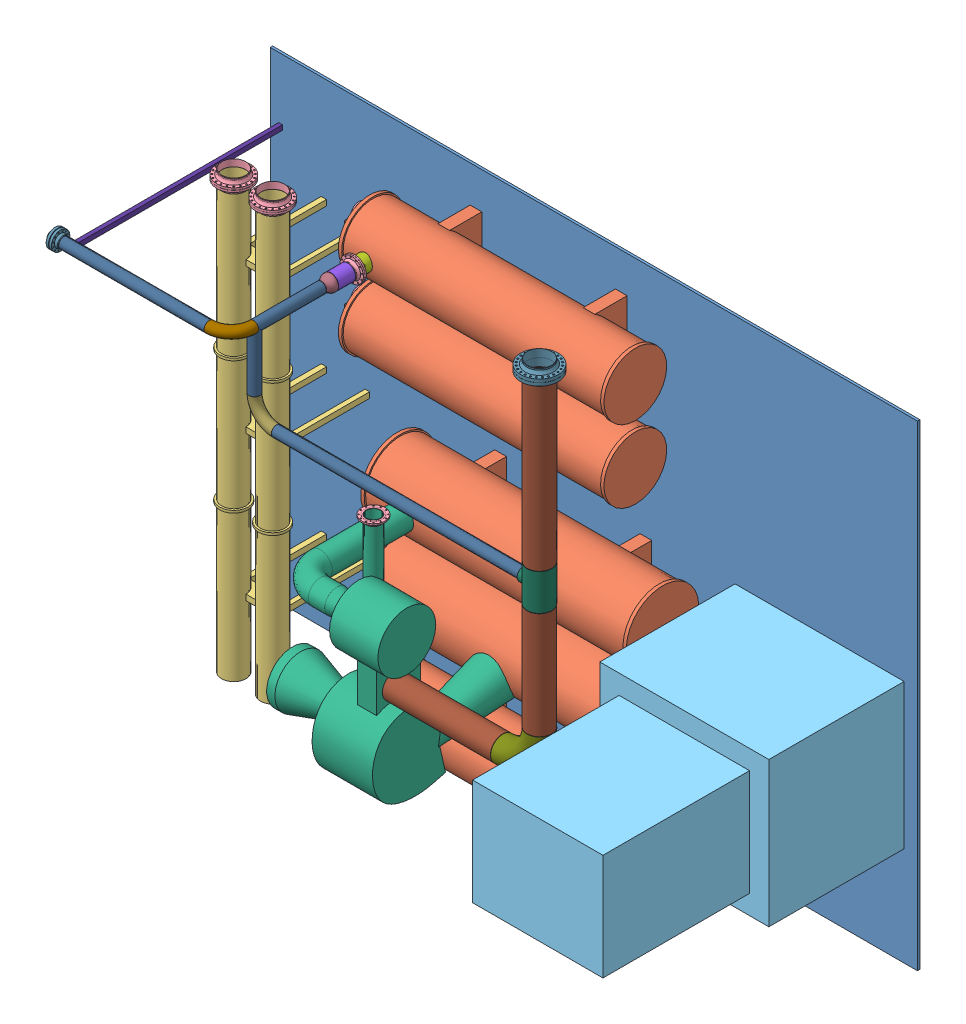
SolidWorks assembly KOMPRESOR-2 SKLOP, configuration Default. Lengths in mm.
Overall size (13601 11029 5885).
47 component instances, 18 part files, 71 mates.
Components (placement in the parent):
- Part2^Assem1-1: Part2^Assem1 [Default] at (-624 250 -240.5401) size (13400 9858 50)
- Rezervoar 1500-1: Rezervoar 1500 [1300] at (150 -3000 714.4599) x (1 0 0) z (0 -1 0) size (5800 1605 1300)
- Rezervoar 1500-2: Rezervoar 1500 [Default] at (150 867 659.4599) x (1 0 0) z (0 -1 0) size (5800 1650 1500)
- Rezervoar 1500-3: Rezervoar 1500 [Default] at (150 -899 659.4599) x (1 0 0) z (0 -1 0) size (5800 1650 1500)
- Rezervoar 1500-4: Rezervoar 1500 [1300] at (-360 3500 714.4599) x (1 0 0) z (0 -1 0) size (5800 1605 1300)
- Rezervoar 1500-5: Rezervoar 1500 [1300] at (-360 5000 714.4599) x (1 0 0) z (0 -1 0) size (5800 1605 1300)
- Kolektori-1: Kolektori [Default] at (-4165 1085.73 1669.4599) x (0 -1 0) z (-1 0 0) size (8880 2204 1392)
- welding neck flange-1: welding neck flange [WNeck Flange 150-NPS8] at (-2898.476 -3170 789.4599) x (0 0 1) z (-1 0 0) size (342.9 342.9 111.61)
- welding neck flange-2: welding neck flange [WNeck Flange 150-NPS8] at (-2898.476 -2830 639.4599) x (0 0 1) z (-1 0 0) size (342.9 342.9 111.61)
- welding neck flange-3: welding neck flange [WNeck Flange 150-NPS8] at (-3408.476 3330 789.4599) x (0 0 1) z (-1 0 0) size (342.9 342.9 111.61)
- welding neck flange-5: welding neck flange [WNeck Flange 150-NPS8] at (-3408.476 3670 639.4599) x (0 0 1) z (-1 0 0) size (342.9 342.9 111.61)
- welding neck flange-6: welding neck flange [WNeck Flange 150-NPS8] at (-3408.476 4830 789.4599) x (0 0 1) z (-1 0 0) size (342.9 342.9 111.61)
- welding neck flange-7: welding neck flange [WNeck Flange 150-NPS8] at (-3408.476 5170 639.4599) x (0 0 1) z (-1 0 0) size (342.9 342.9 111.61)
- welding neck flange-8: welding neck flange [WNeck Flange 150-NPS6] at (-2898.476 -1069 659.46) x (0 0 1) z (-1 0 0) size (279.4 279.4 98.91)
- welding neck flange-9: welding neck flange [WNeck Flange 150-NPS6] at (-2898.476 -729 659.4598) x (0 0 1) z (-1 0 0) size (279.4 279.4 98.91)
- welding neck flange-10: welding neck flange [WNeck Flange 150-NPS6] at (-2898.476 697 659.46) x (0 0 1) z (-1 0 0) size (279.4 279.4 98.91)
- welding neck flange-11: welding neck flange [WNeck Flange 150-NPS6] at (-2898.476 1037 659.4598) x (0 0 1) z (-1 0 0) size (279.4 279.4 98.91)
- Postolje-1: Postolje [Default] at (0 0 2519.4599) (suppressed, hidden)
- MOTOR-1: MOTOR [Default] at (-624 250 -240.5401) size (3500 3000 5835)
- Kompresorsko kolo-1: Kompresorsko kolo [Default] at (0 0.002 -78.038) x (0 0 -1) z (1 0 0) size (3486.15 4337.68 5940.11)
- welding neck flange-25: welding neck flange [WNeck Flange 150-NPS20] at (-4969 5524.206 1669.4599) x (1 0 0) z (0 1 0) size (698.5 698.5 154.28)
- welding neck flange-26: welding neck flange [WNeck Flange 150-NPS20] at (-4165 5524.206 1669.4599) x (1 0 0) z (0 1 0) size (698.5 698.5 154.28)
- welding neck flange-27: welding neck flange [WNeck Flange 150-NPS20] at (-4969 5527.254 1669.4599) x (1 0 0) z (0 -1 0) size (698.5 698.5 154.28)
- welding neck flange-28: welding neck flange [WNeck Flange 150-NPS20] at (-4165 5525.73 1669.4599) x (1 0 0) z (0 -1 0) size (698.5 698.5 154.28)
- welding neck flange-30: welding neck flange [WNeck Flange 150-NPS12] at (-593 2398.478 3154.4599) x (1 0 0) z (0 1 0) size (482.6 482.6 124.31)
- Part2^KOMPRESOR-2 SKLOP-1: Part2^KOMPRESOR-2 SKLOP [Default] at (-360 5000 714.4599) x (-1 0 0) z (0 0 1) size (324.8 324.8 850)
- welding neck flange-33: welding neck flange [WNeck Flange 150-NPS12] at (-2600 5000 1562.9359) size (482.6 482.6 124.31)
- routeAssy3-KOMPRESOR-2 SKLOP-1: routeAssy3-KOMPRESOR-2 SKLOP [Default] at origin size (10012.35 7738.21 2713.51)
  - welding neck flange-1: welding neck flange [WNeck Flange 150-NPS12] at (-2600 5000 1565.9839) x (0.923728 0.383049 0) z (0 0 -1) size (482.6 482.6 124.31)
  - 12inSchedule60-routeAssy3-KOMPRESOR-2 SKLOP-1: 12inSchedule60-routeAssy3-KOMPRESOR-2 SKLOP [12 in, Schedule 60] at (-2600 5000 1678.7599) x (0.707107 0.707107 0) z (0 0 1) size (323.85 323.85 348.4) (virtual)
  - 12inSchedule60_2-routeAssy3-KOMPRESOR-2 SKLOP-1: 12inSchedule60_2-routeAssy3-KOMPRESOR-2 SKLOP [Pipe 12 in, Sch 60] at (-2600 5000 3630.2599) x (0.707107 0.707107 0) z (0 0 -1) size (510.17 510.17 566.67) (virtual)
  - 8inSchedule20_1-routeAssy3-KOMPRESOR-2 SKLOP-1: 8inSchedule20_1-routeAssy3-KOMPRESOR-2 SKLOP [8 in, Schedule 20, 5] at (-2600 5000 2230.3599) x (0.707107 0.707107 0) z (0 0 1) size (218.95 218.95 1408.24)
  - 8inSchedule20_1-routeAssy3-KOMPRESOR-2 SKLOP-2: 8inSchedule20_1-routeAssy3-KOMPRESOR-2 SKLOP [8 in, Schedule 20, 1] at (-3057.2 5000 4087.4599) x (0 0.707107 0.707107) z (-1 0 0) size (218.95 218.95 3010.4)
  - 20inSchedule60-routeAssy3-KOMPRESOR-2 SKLOP-1: 20inSchedule60-routeAssy3-KOMPRESOR-2 SKLOP [20 in, Schedule 60, 3] at (3300 7044.896 3609.4599) x (0.707107 0 0.707107) z (0 -1 0) size (508 508 3315.74)
  - 20inSchedule60-routeAssy3-KOMPRESOR-2 SKLOP-2: 20inSchedule60-routeAssy3-KOMPRESOR-2 SKLOP [20 in, Schedule 60, 1] at (2538 0 3609.4599) x (0 0.707107 0.707107) z (-1 0 0) size (508 508 2238)
  - 20inSchedule60-routeAssy3-KOMPRESOR-2 SKLOP-3: 20inSchedule60-routeAssy3-KOMPRESOR-2 SKLOP [20 in, Schedule 60, 2] at (3300 2967.1563 3609.4599) x (0.707107 0 0.707107) z (0 -1 0) size (508 508 2205.16)
  - 12inSchedule60_3-routeAssy3-KOMPRESOR-2 SKLOP-1: 12inSchedule60_3-routeAssy3-KOMPRESOR-2 SKLOP [Pipe 12 in, Sch 60] at (-2600 3805.3563 3609.4599) x (0.707107 0 0.707107) z (0 1 0) size (510.17 510.17 566.67)
  - 8inSchedule20_1-routeAssy3-KOMPRESOR-2 SKLOP-5: 8inSchedule20_1-routeAssy3-KOMPRESOR-2 SKLOP [8 in, Schedule 20, 2] at (-2142.8 3348.1563 3609.4599) x (0 0.707107 0.707107) z (1 0 0) size (218.95 218.95 5110.06)
  - 8inSchedule20_1-routeAssy3-KOMPRESOR-2 SKLOP-6: 8inSchedule20_1-routeAssy3-KOMPRESOR-2 SKLOP [8 in, Schedule 20] at (-2600 3805.3563 3609.4599) x (0.707107 0 0.707107) z (0 1 0) size (218.95 218.95 1194.64)
  - Backup of reducer-1: Backup of reducer [REDUCER 12 x 8] at (-2600 5000 2027.1599) x (0 0 1) z (0 1 0) size (223.2 323.85 323.85)
  - Backup of welding neck flange-1: Backup of welding neck flange [WNeck Flange 400-NPS8] at (-6184.952 5000 4087.4599) x (0 0 1) z (-1 0 0) size (381 381 133.71)
  - Backup of reducing outlet tee inch-2: Backup of reducing outlet tee inch [RTee Inch20x20x8Sch60] at (3300 3348.1563 3609.4599) x (0 -1 0) z (0 0 -1) size (782 596.74 508)
  - 90deg LR Inch Elbow-1: 90deg LR Inch Elbow [90L LR Inch 20 Sch60] at (2538 762 3609.4599) x (0 1 0) z (0 0 -1) size (1026.09 1026.09 508.2)
  - Backup of welding neck flange-8: Backup of welding neck flange [WNeck Flange 300-NPS20] at (3300 7208.472 3609.4599) x (1 0 0) z (0 -1 0) size (774.7 774.7 172.06)
  - Backup of welding neck flange-9: Backup of welding neck flange [WNeck Flange 300-NPS20] at (3300 7205.424 3609.4599) x (0 0 1) z (0 1 0) size (774.7 774.7 172.06)
  - Backup of welding neck flange-10: Backup of welding neck flange [WNeck Flange 400-NPS8] at (-6197.652 5000 4087.4599) x (0 1 0) z (1 0 0) size (381 381 133.71)
- Part1^KOMPRESOR-2 SKLOP-2: Part1^KOMPRESOR-2 SKLOP [Default] at (-624 250 -240.5401) size (78.44 98.05 4231.12)
Mates (geometry in assembly coordinates):
- Coincident1: coincident anti-aligned: plane of Part2^Assem1-1 through (-6124 -3550 -240.5401) normal (0 0 1); plane of Rezervoar 1500-1 through (-2518.9944 -3000 -240.5401) normal (0 0 -1)
- Coincident3: coincident anti-aligned: plane of Rezervoar 1500-4 through (-3028.9944 3500 -240.5401) normal (0 0 -1); plane of Part2^Assem1-1 through (-6124 -3550 -240.5401) normal (0 0 1)
- Coincident4: coincident anti-aligned: plane of Rezervoar 1500-2 through (-2518.9944 867 -240.5401) normal (0 0 -1); plane of Part2^Assem1-1 through (-6124 -3550 -240.5401) normal (0 0 1)
- Coincident5: coincident anti-aligned: plane of Rezervoar 1500-3 through (-2518.9944 -899 -240.5401) normal (0 0 -1); plane of Part2^Assem1-1 through (-6124 -3550 -240.5401) normal (0 0 1)
- Coincident6: coincident anti-aligned: plane of Rezervoar 1500-5 through (-3028.9944 5000 -240.5401) normal (0 0 -1); plane of Part2^Assem1-1 through (-6124 -3550 -240.5401) normal (0 0 1)
- Distance1: distance = 867 mm anti-aligned: plane of assembly; plane of Rezervoar 1500-2 through (150 867 659.4599) normal (0 -1 0)
- Distance2: distance = 899 mm anti-aligned: plane of assembly; plane of Rezervoar 1500-3 through (150 -899 659.4599) normal (0 -1 0)
- Distance3: distance = 3000 mm anti-aligned: plane of assembly; plane of Rezervoar 1500-1 through (150 -3000 714.4599) normal (0 -1 0)
- Distance4: distance = 3500 mm anti-aligned: plane of assembly; plane of Rezervoar 1500-4 through (-360 3500 714.4599) normal (0 -1 0)
- Distance5: distance = 5000 mm anti-aligned: plane of assembly; plane of Rezervoar 1500-5 through (-360 5000 714.4599) normal (0 -1 0)
- Distance6: distance = 2900 mm aligned: plane of assembly; plane of Rezervoar 1500-1 through (2900 -3000 714.4599) normal (1 0 0)
- Distance7: distance = 2900 mm aligned: plane of assembly; plane of Rezervoar 1500-3 through (2900 -899 659.4599) normal (1 0 0)
- Distance8: distance = 2900 mm aligned: plane of assembly; plane of Rezervoar 1500-2 through (2900 867 659.4599) normal (1 0 0)
- Distance9: distance = 3110 mm anti-aligned: plane of Rezervoar 1500-4 through (-3110 3500 714.4599) normal (-1 0 0); plane of assembly
- Distance10: distance = 3110 mm anti-aligned: plane of Rezervoar 1500-5 through (-3110 5000 714.4599) normal (-1 0 0); plane of assembly
- Coincident17: coincident: line of Part2^Assem1-1 through (-6124 -3550 -240.5401) axis (1 0 0); plane of Rezervoar 1500-1 through (-2518.9944 -3550 -240.5401) normal (0 -1 0)
- Coincident18: coincident anti-aligned: plane of Part2^Assem1-1 through (-6124 -3550 -240.5401) normal (0 0 1); plane of Kolektori-1 through (-4065 1162.4188 -240.5401) normal (0 0 -1)
- Distance11: distance = 5525.73 mm aligned: plane of Kolektori-1 through (-4969 5525.73 1923.4599) normal (0 1 0); plane of assembly
- Distance12: distance = 4715 mm aligned: plane of assembly; cylinder of Kolektori-1 through (-4969 5525.73 1669.4599) axis (0 1 0) radius 254
- Coincident20: coincident: line of Part2^Assem1-1 through (-6124 6308 -240.5401) axis (0 -1 0); plane of Kolektori-1 through (-5069 -1954.27 -240.5401) normal (-1 0 0)
- Concentric11: concentric aligned: cylinder of Rezervoar 1500-1 through (-2900 -3170 789.4599) axis (1 0 0) radius 75; cylinder of welding neck flange-1 through (-2900 -3170 789.4599) axis (1 0 0) radius 123.063
- Coincident211: coincident aligned: plane of Rezervoar 1500-1 through (-2900 -3170 789.4599) normal (-1 0 0); plane of welding neck flange-1 through (-2900 -3170 789.4599) normal (-1 0 0)
- Concentric21: concentric aligned: cylinder of Rezervoar 1500-1 through (-2900 -2830 639.4599) axis (1 0 0) radius 75; cylinder of welding neck flange-2 through (-2900 -2830 639.4599) axis (1 0 0) radius 123.063
- Coincident221: coincident aligned: plane of Rezervoar 1500-1 through (-2900 -2830 639.4599) normal (-1 0 0); plane of welding neck flange-2 through (-2900 -2830 639.4599) normal (-1 0 0)
- Concentric31: concentric aligned: cylinder of Rezervoar 1500-4 through (-3410 3330 789.4599) axis (1 0 0) radius 75; cylinder of welding neck flange-3 through (-3410 3330 789.4599) axis (1 0 0) radius 123.063
- Coincident231: coincident aligned: plane of Rezervoar 1500-4 through (-3410 3330 789.4599) normal (-1 0 0); plane of welding neck flange-3 through (-3410 3330 789.4599) normal (-1 0 0)
- Concentric51: concentric aligned: cylinder of Rezervoar 1500-4 through (-3410 3670 639.4599) axis (1 0 0) radius 85; cylinder of welding neck flange-5 through (-3410 3670 639.4599) axis (1 0 0) radius 123.063
- Coincident251: coincident aligned: plane of Rezervoar 1500-4 through (-3410 3670 639.4599) normal (-1 0 0); plane of welding neck flange-5 through (-3410 3670 639.4599) normal (-1 0 0)
- Concentric61: concentric aligned: cylinder of Rezervoar 1500-5 through (-3410 4830 789.4599) axis (1 0 0) radius 75; cylinder of welding neck flange-6 through (-3410 4830 789.4599) axis (1 0 0) radius 123.063
- Coincident261: coincident aligned: plane of Rezervoar 1500-5 through (-3410 4830 789.4599) normal (-1 0 0); plane of welding neck flange-6 through (-3410 4830 789.4599) normal (-1 0 0)
- Concentric71: concentric aligned: cylinder of Rezervoar 1500-5 through (-3410 5170 639.4599) axis (1 0 0) radius 75; cylinder of welding neck flange-7 through (-3410 5170 639.4599) axis (1 0 0) radius 123.063
- Coincident271: coincident aligned: plane of Rezervoar 1500-5 through (-3410 5170 639.4599) normal (-1 0 0); plane of welding neck flange-7 through (-3410 5170 639.4599) normal (-1 0 0)
- Concentric81: concentric aligned: cylinder of Rezervoar 1500-3 through (-2900 -1069 659.46) axis (1 0 0) radius 100; cylinder of welding neck flange-8 through (-2900 -1069 659.46) axis (1 0 0) radius 96.012
- Coincident281: coincident aligned: plane of Rezervoar 1500-3 through (-2900 -1069 659.46) normal (-1 0 0); plane of welding neck flange-8 through (-2900 -1069 659.46) normal (-1 0 0)
- Concentric91: concentric aligned: cylinder of Rezervoar 1500-3 through (-2900 -729 659.4598) axis (1 0 0) radius 100; cylinder of welding neck flange-9 through (-2900 -729 659.4598) axis (1 0 0) radius 96.012
- Coincident291: coincident aligned: plane of Rezervoar 1500-3 through (-2900 -729 659.4598) normal (-1 0 0); plane of welding neck flange-9 through (-2900 -729 659.4598) normal (-1 0 0)
- Concentric101: concentric aligned: cylinder of Rezervoar 1500-2 through (-2900 697 659.46) axis (1 0 0) radius 110; cylinder of welding neck flange-10 through (-2900 697 659.46) axis (1 0 0) radius 96.012
- Coincident301: coincident aligned: plane of Rezervoar 1500-2 through (-2900 697 659.46) normal (-1 0 0); plane of welding neck flange-10 through (-2900 697 659.46) normal (-1 0 0)
- Concentric111: concentric aligned: cylinder of Rezervoar 1500-2 through (-2900 1037 659.4598) axis (1 0 0) radius 110; cylinder of welding neck flange-11 through (-2900 1037 659.4598) axis (1 0 0) radius 96.012
- Coincident311: coincident aligned: plane of Rezervoar 1500-2 through (-2900 1037 659.4598) normal (-1 0 0); plane of welding neck flange-11 through (-2900 1037 659.4598) normal (-1 0 0)
- Distance13: distance = 2810 mm aligned: plane of Postolje-1 through (-3420 -3750 2569.4599) normal (0 0 1); plane of Part2^Assem1-1 through (-6124 -3550 -240.5401) normal (0 0 1)
- Distance14: distance = 8530 mm: line of Postolje-1 through (8530 -2750 2569.4599) axis (0 1 0); plane of assembly
- Distance15: distance = 2750 mm: line of Postolje-1 through (2140 -2750 2569.4599) axis (1 0 0); plane of assembly
- InPlace1: in place: line of ? through (-6030 -3200 -30.5401) axis (0 0 1); plane of ? through (0 0 -30.5401) normal (0 0 1); moOrthogonalPlaneRef_w of ? through (-6030 -3200 -30.5401) axis (0 0 1); plane of ? through (0 0 -30.5401) normal (0 1 0); line of ? through (-6030 -3200 -30.5401) axis (0 0 1); plane of ? through (0 0 -30.5401) normal (1 0 0); plane of ? through (-6124 -3550 -240.5401) normal (0 0 1); unknown of ?
- Coincident322: coincident aligned: plane of Part2^Assem1-1; plane of MOTOR-1
- Coincident323: coincident aligned: moOrthogonalPlaneRef_w of Part2^Assem1-1 through (-624 250 -240.5401) axis (0 1 0); plane of MOTOR-1 through (-624 250 -240.5401) normal (0 1 0)
- Coincident324: coincident anti-aligned: moOrthogonalPlaneRef_w of Part2^Assem1-1 through (-624 250 -240.5401) axis (-1 0 0); plane of MOTOR-1 through (-624 250 -240.5401) normal (1 0 0)
- Concentric11971: concentric anti-aligned: cylinder of Kolektori-1 through (-4969 5525.73 1669.4599) axis (0 1 0) radius 254; cylinder of welding neck flange-25 through (-4969 5525.73 1669.4599) axis (0 -1 0) radius 279.4
- Coincident32271: coincident aligned: plane of Kolektori-1 through (-4969 5525.73 1923.4599) normal (0 1 0); plane of welding neck flange-25 through (-4969 5525.73 1669.4599) normal (0 1 0)
- Concentric11981: concentric anti-aligned: cylinder of Kolektori-1 through (-4165 5525.73 1669.4599) axis (0 1 0) radius 244; cylinder of welding neck flange-26 through (-4165 5525.73 1669.4599) axis (0 -1 0) radius 279.4
- Coincident32281: coincident aligned: plane of Kolektori-1 through (-4165 5525.73 1923.4599) normal (0 1 0); plane of welding neck flange-26 through (-4165 5525.73 1669.4599) normal (0 1 0)
- Concentric11991: concentric aligned: cylinder of Kolektori-1 through (-4969 5525.73 1669.4599) axis (0 1 0) radius 244; cylinder of welding neck flange-27 through (-4969 5525.73 1669.4599) axis (0 1 0) radius 279.4
- Coincident32291: coincident anti-aligned: plane of Kolektori-1 through (-4969 5525.73 1923.4599) normal (0 1 0); plane of welding neck flange-27 through (-4969 5525.73 1669.4599) normal (0 -1 0)
- Concentric12001: concentric aligned: cylinder of welding neck flange-26 through (-4165 4495.2298 1669.4599) axis (0 1 0) radius 349.25; cylinder of welding neck flange-28 through (-4165 5524.206 1669.4599) axis (0 1 0) radius 279.4
- Coincident32301: coincident anti-aligned: plane of welding neck flange-26 through (-4165 5524.206 1669.4599) normal (0 1 0); plane of welding neck flange-28 through (-4165 5524.206 1669.4599) normal (0 -1 0)
- Coincident3231: coincident aligned: plane of Kompresorsko kolo-1 through (0 0.002 -78.038) normal (1 0 0); plane of assembly
- Distance16: distance = 365.4 mm aligned: plane of assembly; cylinder of Kompresorsko kolo-1 through (-5750.6573 -899.498 3604.4579) axis (1 0 0) radius 534.098
- Distance17: distance = 3310.9 mm anti-aligned: plane of Part2^Assem1-1 through (-6124 -3550 -240.5401) normal (0 0 1); cylinder of Kompresorsko kolo-1 through (-5750.6573 -899.498 3604.4579) axis (1 0 0) radius 534.098
- InPlace3: in place: plane of Rezervoar 1500-5 through (-360 5000 714.4599) normal (0 0 1); plane of ? through (0 0 714.4599) normal (0 0 1); plane of Rezervoar 1500-5 through (-360 5000 714.4599) normal (0 0 1); plane of ? through (0 0 714.4599) normal (0 1 0); plane of Rezervoar 1500-5 through (-360 5000 714.4599) normal (0 0 1); plane of ? through (0 0 714.4599) normal (1 0 0); plane of Rezervoar 1500-5 through (-360 5000 714.4599) normal (0 0 1); unknown of Part2^KOMPRESOR-2 SKLOP-1
- Coincident3239: coincident aligned: plane of Rezervoar 1500-5; plane of Part2^KOMPRESOR-2 SKLOP-1
- Coincident3240: coincident aligned: moOrthogonalPlaneRef_w of Rezervoar 1500-5 through (-360 5000 714.4599) axis (0 -1 0); plane of Part2^KOMPRESOR-2 SKLOP-1
- Coincident3241: coincident anti-aligned: moOrthogonalPlaneRef_w of Rezervoar 1500-5 through (-360 5000 714.4599) axis (1 0 0); plane of Part2^KOMPRESOR-2 SKLOP-1
- Concentric12051: concentric aligned: cylinder of Part2^KOMPRESOR-2 SKLOP-1 through (-2600 5000 1564.4599) axis (0 0 -1) radius 162.4; cylinder of welding neck flange-33 through (-2600 5000 1564.4599) axis (0 0 -1) radius 182.626
- Coincident32421: coincident aligned: plane of Part2^KOMPRESOR-2 SKLOP-1 through (-2600 5000 1564.4599) normal (0 0 1); plane of welding neck flange-33 through (-2600 5000 1564.4599) normal (0 0 1)
- Coincident32462: coincident aligned: plane of Kompresorsko kolo-1 through (-593 2400.002 3154.4599) normal (0 1 0); plane of welding neck flange-30 through (-593 2400.002 3154.4599) normal (0 1 0)
- Concentric120933: concentric anti-aligned: cylinder of Kompresorsko kolo-1 through (-593 2400.002 3154.4599) axis (0 -1 0) radius 152.4; cylinder of welding neck flange-30 through (-593 1685.7525 3154.4599) axis (0 1 0) radius 241.3
- InPlace4: in place: plane of ? through (-6124 -3550 -240.5401) normal (0 0 1); plane of ? through (0 0 -240.5401) normal (0 0 1); plane of ? through (-6124 -3550 -240.5401) normal (0 0 1); plane of ? through (0 0 -240.5401) normal (0 1 0); plane of ? through (-6124 -3550 -240.5401) normal (0 0 1); plane of ? through (0 0 -240.5401) normal (1 0 0); plane of ? through (-6124 -3550 -240.5401) normal (0 0 1); unknown of ?
- Coincident324643: coincident aligned: plane of Part2^Assem1-1; plane of Part1^KOMPRESOR-2 SKLOP-2
- Coincident324644: coincident aligned: moOrthogonalPlaneRef_w of Part2^Assem1-1 through (-624 250 -240.5401) normal (0 1 0); plane of Part1^KOMPRESOR-2 SKLOP-2 through (-624 250 -240.5401) normal (0 1 0)
- Coincident324645: coincident anti-aligned: plane of ? through (-624 250 -240.5401) normal (-1 0 0); plane of ? through (-624 250 -240.5401) normal (1 0 0)
- PLANE1: unknown: plane of ? through (-6124 -3550 -240.5401) normal (0 0 1); unknown of routeAssy3-KOMPRESOR-2 SKLOP-1/8inSchedule20_1-routeAssy3-KOMPRESOR-2 SKLOP-2
